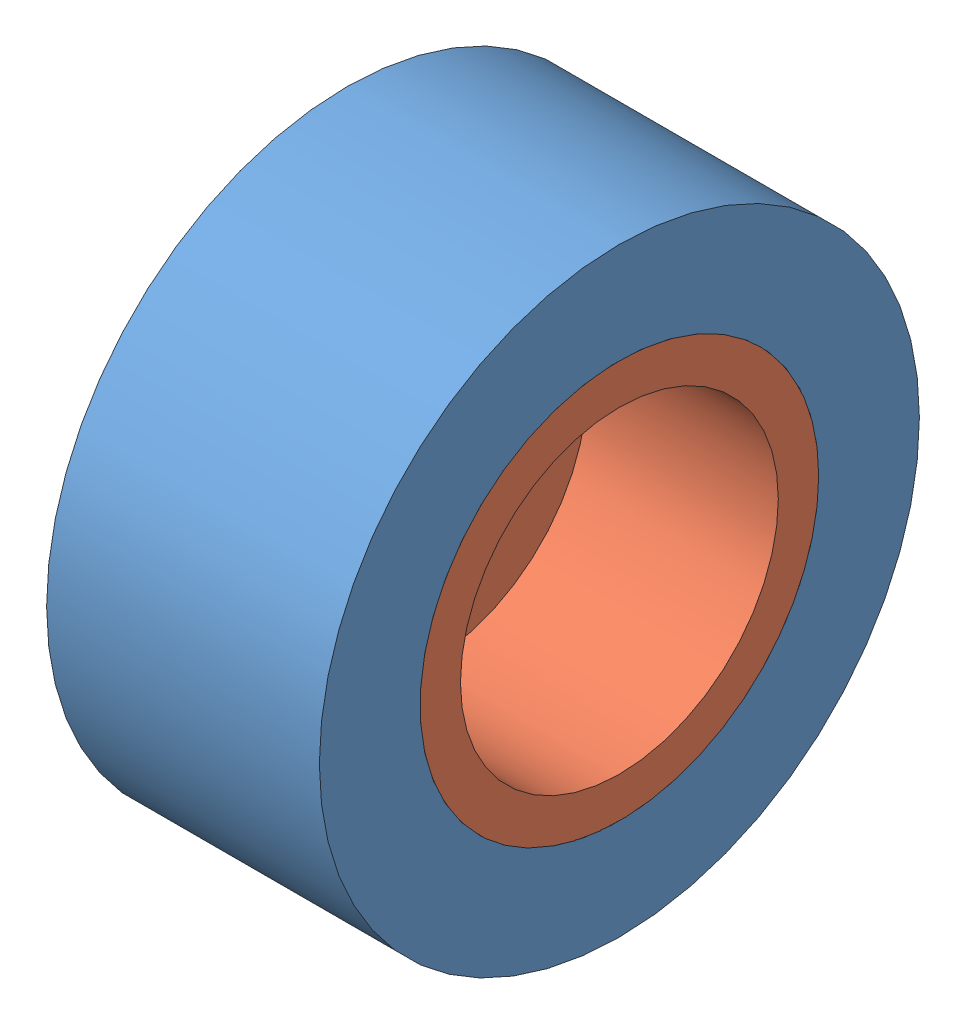
SolidWorks assembly Assemblage4, configuration Défaut. Lengths in mm.
Overall size (16.9 28.6 28.6).
2 component instances, 2 part files, 2 mates.
Components (placement in the parent):
- Roue1-1: Roue1 [Défaut] at (-7.3778 0.3244 28.6) size (13 28.6 28.6)
- Roue2-1: Roue2 [Défaut] at (-7.6778 0.3244 28.6) x (0 -1 0) z (0 0 1) size (19 16.9 19)
Mates (geometry in assembly coordinates):
- Coaxiale1: concentric: cylinder of Roue1-1 through (-7.3778 0.3244 28.6) axis (1 0 0) radius 9.5; cylinder of Roue2-1 through (5.6222 0.3244 28.6) axis (-1 0 0) radius 9.5
- Coïncidente1: coincident: circle of Roue1-1; circle of Roue2-1
